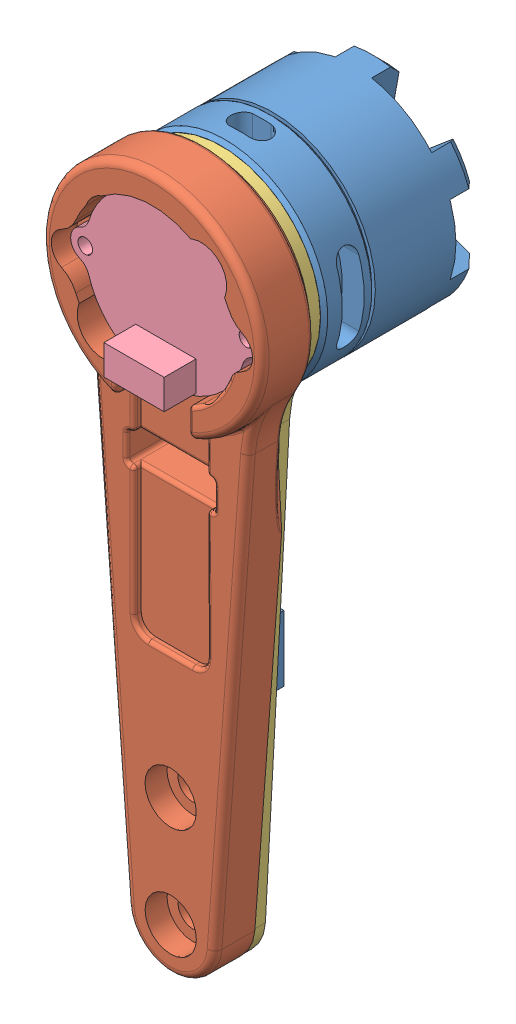
SolidWorks assembly 腿, configuration 默认. Lengths in mm.
Overall size (30.08 96.03 35.85).
4 component instances, 4 part files, 9 mates.
Components (placement in the parent):
- Motor2206-1: Motor2206 [默认] at origin size (28 64.89 25.9)
- leg1b-1: leg1b [默认] at (0.0056 -0.0056 8.5) x (-0.000836 1 0) z (0 0 1) size (96 30 8.18)
- leg1a-3: leg1a [默认] at (0 0 7) x (0 1 0) z (0 0 1) size (94.5 27 1.5)
- 编码器-1: 编码器 [默认] at (0.0056 -0.0056 14.6) x (1 0.000836 0) z (0 0 -1) size (26 22 7.42)
Mates (geometry in assembly coordinates):
- 重合1: coordinate: point of Motor2206-1
- 重合8: coincident anti-aligned: plane of Motor2206-1 through (0 0 7) normal (0 0 1); plane of leg1a-3 through (0 -75 7) normal (0 0 -1)
- 同心5: concentric aligned: circle of Motor2206-1; circle of leg1a-3
- 同心6: concentric aligned: circle of Motor2206-1; circle of leg1a-3
- 重合11: coincident anti-aligned: plane of leg1b-1 through (0.0683 -75.0056 8.5) normal (0 0 -1); plane of leg1a-3 through (0 -75 8.5) normal (0 0 1)
- 同心7: concentric aligned: circle of leg1b-1; circle of leg1a-3
- 重合28: coincident anti-aligned: plane of leg1b-1 through (14.0839 5.8564 13) normal (0 0 1); plane of 编码器-1 through (11.7344 -1.8589 13) normal (0 0 -1)
- 同心16: concentric anti-aligned: circle of leg1b-1; circle of 编码器-1
- 同心17: concentric anti-aligned: circle of leg1b-1; circle of 编码器-1
